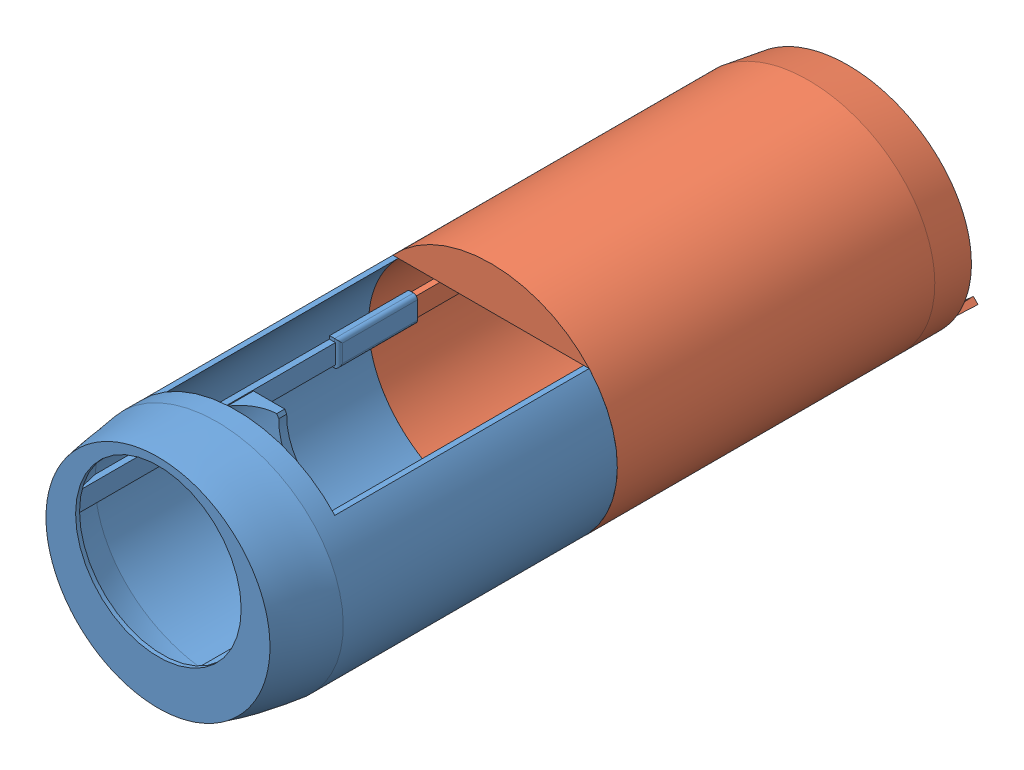
SolidWorks assembly Assem1, configuration Default. Lengths in mm.
Overall size (66.5 61.66 186.51).
2 component instances, 2 part files, 1 mates.
Components (placement in the parent):
- nose_front-1: nose_front [Default] at (-29.6416 5.1807 -17.6667) size (65.28 60.18 96.02)
- nose_rear-1: nose_rear [Default] at (-29.6416 5.1807 -97.6667) size (66.5 60.13 100.52)
Mates (geometry in assembly coordinates):
- Tangent1: tangent: curve of nose_front-1; curve of nose_rear-1
